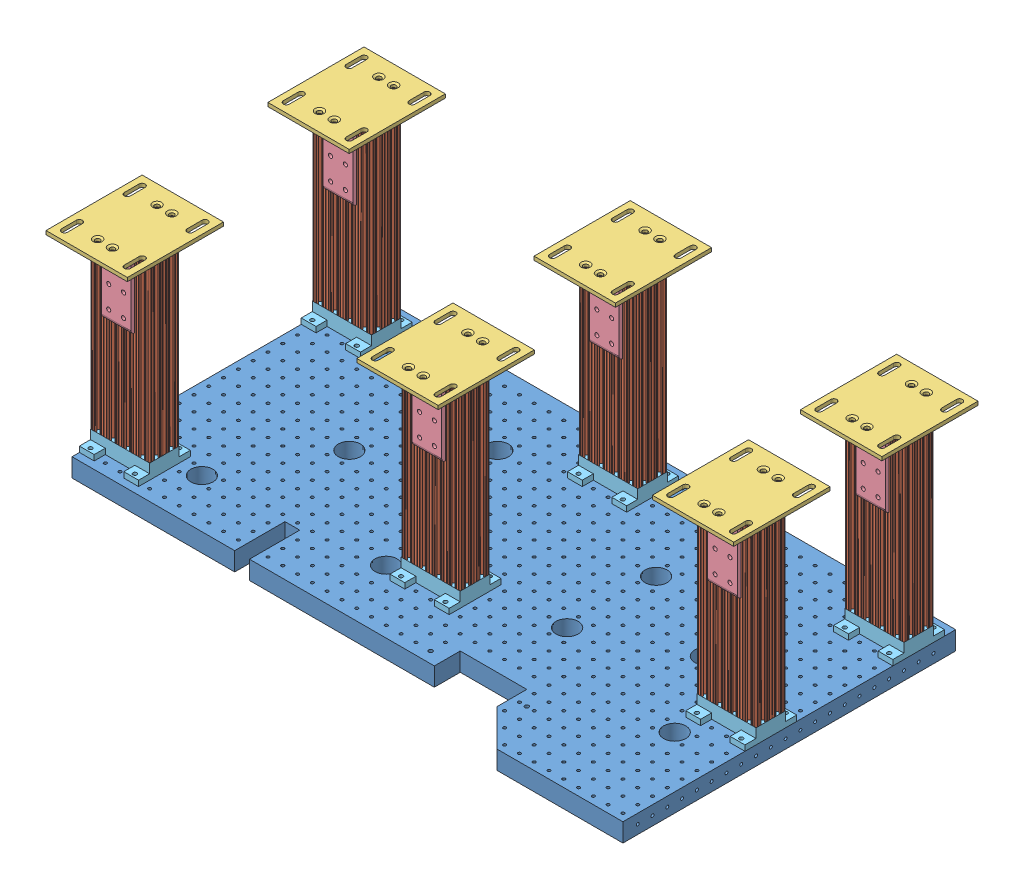
SolidWorks assembly breadboard 2 assembly, configuration Default. Lengths in mm.
Overall size (1054.1 371.48 590.75).
43 component instances, 5 part files, 18 mates.
Components (placement in the parent):
- Breadboard1-1: Breadboard1 [Default] at (-194.6573 17.0814 91.1131) size (1016 31.75 571.5)
- breadboard support leg assembly-1: breadboard support leg assembly [Default] at (-182.8187 304.0452 -389.5924) x (0 0 -1) z (0 1 0) size (165.1 139.7 339.72)
  - 8020-2040 leg for breadboard support-1: 8020-2040 leg for breadboard support [Default] at (-48.9055 -77.0614 78.1612) size (50.8 101.6 307.98)
  - 8020-2387-DEFAULT-1: 8020-2387-DEFAULT [Default] at (-34.9863 -22.6888 91.8816) x (0 1 0) z (-1 0 0) size (139.7 133.35 165.1)
    - 8020-2387-DEFAULT_238708-1: 8020-2387-DEFAULT_238708 [Default] at (-67.1549 7.3704 27.8119) size (139.7 6.35 165.1)
    - 8020-2387-DEFAULT_238509-1: 8020-2387-DEFAULT_238509 [Default] at (9.1264 0.0214 49.7635) x (0 0 1) z (-1 0 0) size (50.8 127 50.8)
    - 8020-2387-DEFAULT_238509-2: 8020-2387-DEFAULT_238509 [Default] at (-41.6736 0.0214 -46.9187) x (0 0 -1) z (1 0 0) size (50.8 127 50.8)
  - breadboard support leg top bracket-1: breadboard support leg top bracket [Default] at (-61.6055 -89.7614 -229.8138) x (0 1 0) z (-1 0 0) size (101.6 25.4 88.9)
- breadboard support leg assembly-3: breadboard support leg assembly [Default] at (352.3041 304.0452 -317.1813) x (0 0 1) z (0 1 0) size (165.1 139.7 339.72)
  - 8020-2040 leg for breadboard support-1: 8020-2040 leg for breadboard support [Default] at (-48.9055 -77.0614 78.1612) size (50.8 101.6 307.98)
  - 8020-2387-DEFAULT-1: 8020-2387-DEFAULT [Default] at (-34.9863 -22.6888 91.8816) x (0 1 0) z (-1 0 0) size (139.7 133.35 165.1)
    - 8020-2387-DEFAULT_238708-1: 8020-2387-DEFAULT_238708 [Default] at (-67.1549 7.3704 27.8119) size (139.7 6.35 165.1)
    - 8020-2387-DEFAULT_238509-1: 8020-2387-DEFAULT_238509 [Default] at (9.1264 0.0214 49.7635) x (0 0 1) z (-1 0 0) size (50.8 127 50.8)
    - 8020-2387-DEFAULT_238509-2: 8020-2387-DEFAULT_238509 [Default] at (-41.6736 0.0214 -46.9187) x (0 0 -1) z (1 0 0) size (50.8 127 50.8)
  - breadboard support leg top bracket-1: breadboard support leg top bracket [Default] at (-61.6055 -89.7614 -229.8138) x (0 1 0) z (-1 0 0) size (101.6 25.4 88.9)
- breadboard support leg assembly-4: breadboard support leg assembly [Default] at (274.3813 304.0452 -135.5924) x (0 0 -1) z (0 1 0) size (165.1 139.7 339.72)
  - 8020-2040 leg for breadboard support-1: 8020-2040 leg for breadboard support [Default] at (-48.9055 -77.0614 78.1612) size (50.8 101.6 307.98)
  - 8020-2387-DEFAULT-1: 8020-2387-DEFAULT [Default] at (-34.9863 -22.6888 91.8816) x (0 1 0) z (-1 0 0) size (139.7 133.35 165.1)
    - 8020-2387-DEFAULT_238708-1: 8020-2387-DEFAULT_238708 [Default] at (-67.1549 7.3704 27.8119) size (139.7 6.35 165.1)
    - 8020-2387-DEFAULT_238509-1: 8020-2387-DEFAULT_238509 [Default] at (9.1264 0.0214 49.7635) x (0 0 1) z (-1 0 0) size (50.8 127 50.8)
    - 8020-2387-DEFAULT_238509-2: 8020-2387-DEFAULT_238509 [Default] at (-41.6736 0.0214 -46.9187) x (0 0 -1) z (1 0 0) size (50.8 127 50.8)
  - breadboard support leg top bracket-1: breadboard support leg top bracket [Default] at (-61.6055 -89.7614 -229.8138) x (0 1 0) z (-1 0 0) size (101.6 25.4 88.9)
- breadboard support leg assembly-5: breadboard support leg assembly [Default] at (-104.8959 304.0452 -12.3813) x (0 0 1) z (0 1 0) size (165.1 139.7 339.72)
  - 8020-2040 leg for breadboard support-1: 8020-2040 leg for breadboard support [Default] at (-48.9055 -77.0614 78.1612) size (50.8 101.6 307.98)
  - 8020-2387-DEFAULT-1: 8020-2387-DEFAULT [Default] at (-34.9863 -22.6888 91.8816) x (0 1 0) z (-1 0 0) size (139.7 133.35 165.1)
    - 8020-2387-DEFAULT_238708-1: 8020-2387-DEFAULT_238708 [Default] at (-67.1549 7.3704 27.8119) size (139.7 6.35 165.1)
    - 8020-2387-DEFAULT_238509-1: 8020-2387-DEFAULT_238509 [Default] at (9.1264 0.0214 49.7635) x (0 0 1) z (-1 0 0) size (50.8 127 50.8)
    - 8020-2387-DEFAULT_238509-2: 8020-2387-DEFAULT_238509 [Default] at (-41.6736 0.0214 -46.9187) x (0 0 -1) z (1 0 0) size (50.8 127 50.8)
  - breadboard support leg top bracket-1: breadboard support leg top bracket [Default] at (-61.6055 -89.7614 -229.8138) x (0 1 0) z (-1 0 0) size (101.6 25.4 88.9)
- breadboard support leg assembly-6: breadboard support leg assembly [Default] at (-640.0187 304.0452 -8.5924) x (0 0 -1) z (0 1 0) size (165.1 139.7 339.72)
  - 8020-2040 leg for breadboard support-1: 8020-2040 leg for breadboard support [Default] at (-48.9055 -77.0614 78.1612) size (50.8 101.6 307.98)
  - 8020-2387-DEFAULT-1: 8020-2387-DEFAULT [Default] at (-34.9863 -22.6888 91.8816) x (0 1 0) z (-1 0 0) size (139.7 133.35 165.1)
    - 8020-2387-DEFAULT_238708-1: 8020-2387-DEFAULT_238708 [Default] at (-67.1549 7.3704 27.8119) size (139.7 6.35 165.1)
    - 8020-2387-DEFAULT_238509-1: 8020-2387-DEFAULT_238509 [Default] at (9.1264 0.0214 49.7635) x (0 0 1) z (-1 0 0) size (50.8 127 50.8)
    - 8020-2387-DEFAULT_238509-2: 8020-2387-DEFAULT_238509 [Default] at (-41.6736 0.0214 -46.9187) x (0 0 -1) z (1 0 0) size (50.8 127 50.8)
  - breadboard support leg top bracket-1: breadboard support leg top bracket [Default] at (-61.6055 -89.7614 -229.8138) x (0 1 0) z (-1 0 0) size (101.6 25.4 88.9)
- breadboard support leg assembly-7: breadboard support leg assembly [Default] at (-640.0187 304.0452 -389.5924) x (0 0 -1) z (0 1 0) size (165.1 139.7 339.72)
  - 8020-2040 leg for breadboard support-1: 8020-2040 leg for breadboard support [Default] at (-48.9055 -77.0614 78.1612) size (50.8 101.6 307.98)
  - 8020-2387-DEFAULT-1: 8020-2387-DEFAULT [Default] at (-34.9863 -22.6888 91.8816) x (0 1 0) z (-1 0 0) size (139.7 133.35 165.1)
    - 8020-2387-DEFAULT_238708-1: 8020-2387-DEFAULT_238708 [Default] at (-67.1549 7.3704 27.8119) size (139.7 6.35 165.1)
    - 8020-2387-DEFAULT_238509-1: 8020-2387-DEFAULT_238509 [Default] at (9.1264 0.0214 49.7635) x (0 0 1) z (-1 0 0) size (50.8 127 50.8)
    - 8020-2387-DEFAULT_238509-2: 8020-2387-DEFAULT_238509 [Default] at (-41.6736 0.0214 -46.9187) x (0 0 -1) z (1 0 0) size (50.8 127 50.8)
  - breadboard support leg top bracket-1: breadboard support leg top bracket [Default] at (-61.6055 -89.7614 -229.8138) x (0 1 0) z (-1 0 0) size (101.6 25.4 88.9)
Mates (geometry in assembly coordinates):
- Coincident1: coincident anti-aligned: plane of Breadboard1-1 through (-194.6573 48.8314 -416.8869) normal (0 1 0); plane of breadboard support leg assembly-1/breadboard support leg top bracket-1 through (-93.0573 48.8314 -378.7869) normal (0 -1 0)
- Parallel2: parallel aligned: plane of Breadboard1-1 through (-651.8573 17.0814 -416.8869) normal (-1 0 0); plane of breadboard support leg assembly-1/breadboard support leg top bracket-1 through (-194.6573 48.8314 -327.9869) normal (-1 0 0)
- Coincident8: coincident anti-aligned: plane of Breadboard1-1 through (-194.6573 48.8314 -416.8869) normal (0 1 0); plane of breadboard support leg assembly-5/breadboard support leg top bracket-1 through (-194.6573 48.8314 -23.1869) normal (0 -1 0)
- Parallel4: parallel anti-aligned: plane of Breadboard1-1 through (-194.6573 48.8314 -416.8869) normal (0 0 -1); plane of breadboard support leg assembly-5/breadboard support leg top bracket-1 through (-93.0573 58.3564 -4.1369) normal (0 0 1)
- Coincident13: coincident anti-aligned: plane of Breadboard1-1 through (-194.6573 48.8314 -416.8869) normal (0 1 0); plane of breadboard support leg assembly-4/breadboard support leg top bracket-1 through (364.1427 48.8314 -124.7869) normal (0 -1 0)
- Coincident16: coincident anti-aligned: plane of Breadboard1-1 through (-194.6573 48.8314 -416.8869) normal (0 1 0); plane of breadboard support leg assembly-3/breadboard support leg top bracket-1 through (262.5427 48.8314 -327.9869) normal (0 -1 0)
- Coincident17: coincident aligned: plane of Breadboard1-1 through (364.1427 48.8314 91.1131) normal (1 0 0); plane of breadboard support leg assembly-3/breadboard support leg top bracket-1 through (364.1427 48.8314 -378.7869) normal (1 0 0)
- Concentric2: concentric anti-aligned: circle of Breadboard1-1; circle of breadboard support leg assembly-3/breadboard support leg top bracket-1
- Concentric4: concentric anti-aligned: circle of breadboard support leg assembly-5/breadboard support leg top bracket-1; circle of Breadboard1-1
- Concentric6: concentric anti-aligned: circle of Breadboard1-1; circle of breadboard support leg assembly-1/breadboard support leg top bracket-1
- Concentric7: concentric anti-aligned: circle of breadboard support leg assembly-4/breadboard support leg top bracket-1; circle of Breadboard1-1
- Parallel5: parallel aligned: plane of Breadboard1-1 through (364.1427 48.8314 91.1131) normal (1 0 0); plane of breadboard support leg assembly-4/breadboard support leg top bracket-1 through (364.1427 48.8314 -73.9869) normal (1 0 0)
- Coincident19: coincident anti-aligned: plane of Breadboard1-1 through (-194.6573 48.8314 -416.8869) normal (0 1 0); plane of breadboard support leg assembly-6/breadboard support leg top bracket-1 through (-550.2573 48.8314 2.2131) normal (0 -1 0)
- Concentric8: concentric anti-aligned: circle of Breadboard1-1; circle of breadboard support leg assembly-6/breadboard support leg top bracket-1
- Parallel6: parallel aligned: plane of Breadboard1-1 through (-651.8573 17.0814 -416.8869) normal (-1 0 0); plane of breadboard support leg assembly-6/breadboard support leg top bracket-1 through (-651.8573 48.8314 53.0131) normal (-1 0 0)
- Coincident21: coincident anti-aligned: plane of Breadboard1-1 through (-194.6573 48.8314 -416.8869) normal (0 1 0); plane of breadboard support leg assembly-7/breadboard support leg top bracket-1 through (-550.2573 48.8314 -378.7869) normal (0 -1 0)
- Concentric9: concentric anti-aligned: circle of Breadboard1-1; circle of breadboard support leg assembly-7/breadboard support leg top bracket-1
- Parallel7: parallel aligned: plane of Breadboard1-1 through (-651.8573 17.0814 -416.8869) normal (-1 0 0); plane of breadboard support leg assembly-7/breadboard support leg top bracket-1 through (-651.8573 48.8314 -327.9869) normal (-1 0 0)
